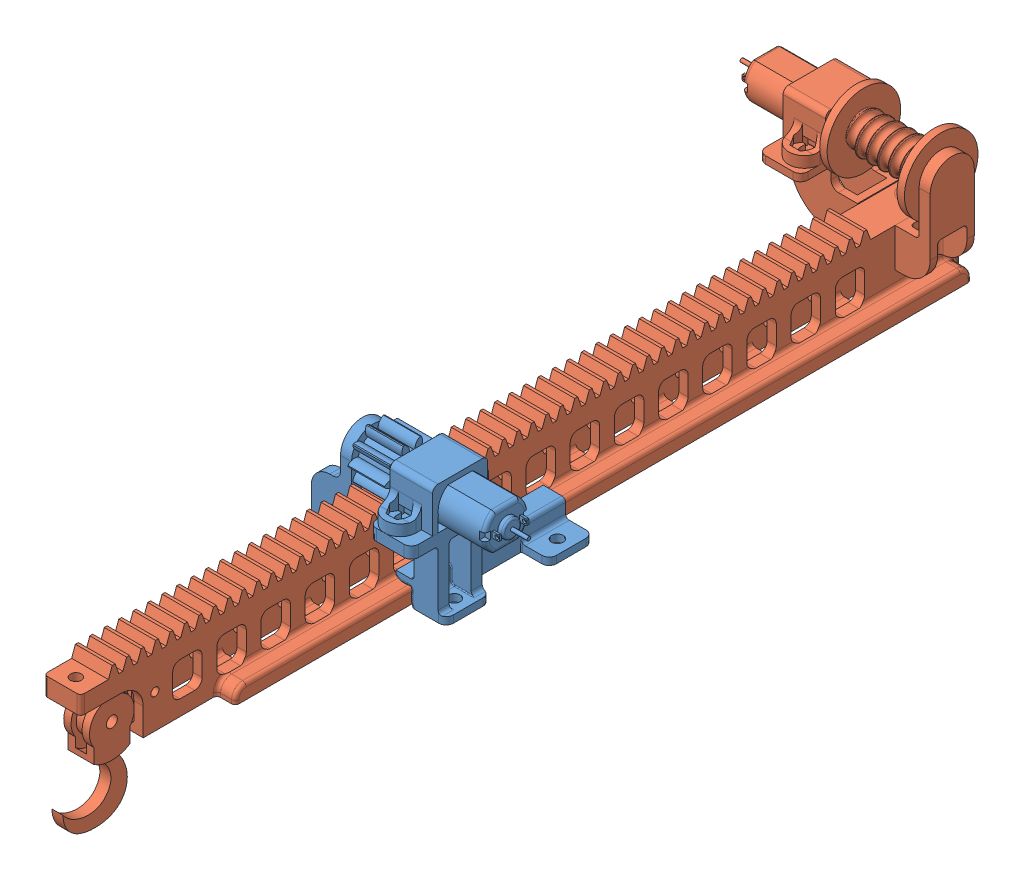
SolidWorks assembly Crane Assembly, configuration Default. Lengths in mm.
2 component instances, 2 part files, 4 mates.
Components (placement in the parent):
- crane-extension-gear-1: crane-extension-gear [Metric - Spur gear 1.25M 10T 20PA 12FW] at (-6.6937 37.1671 63.3427) size (56.9 33.76 47.34)
- crane-jib-1: crane-jib [Metric - Rack-spur - rectangular 1.25M 20PA 10FW 20PH 220L---SAll] at (3.3173 11.0271 146.4367) x (0 0 -1) z (1 0 0) size (242.23 59.74 57.14)
Mates (geometry in assembly coordinates):
- Parallel1: parallel aligned: plane of crane-extension-gear-1 through (-8.2572 37.1671 29.3427) normal (1 0 0); plane of crane-jib-1 through (3.3173 32.2771 146.4367) normal (1 0 0)
- Coincident2: coincident aligned: plane of crane-extension-gear-1 through (-10.1937 11.0271 66.3427) normal (0 -1 0); plane of crane-jib-1 through (-6.6827 11.0271 146.4367) normal (0 -1 0)
- RackPinionMate1: rack pinion = 9.373 mm: plane of crane-jib-1 through (-6.6827 32.2771 146.4367) normal (0 1 0); cylinder of crane-extension-gear-1 through (3.3063 37.1671 63.3427) axis (-1 0 0) radius 4.6865
- Distance1: distance = 10.1821 mm aligned: plane of crane-jib-1 through (8.3173 11.0271 116.4367) normal (1 0 0); plane of crane-extension-gear-1 through (18.4994 16.7271 41.3427) normal (1 0 0)
